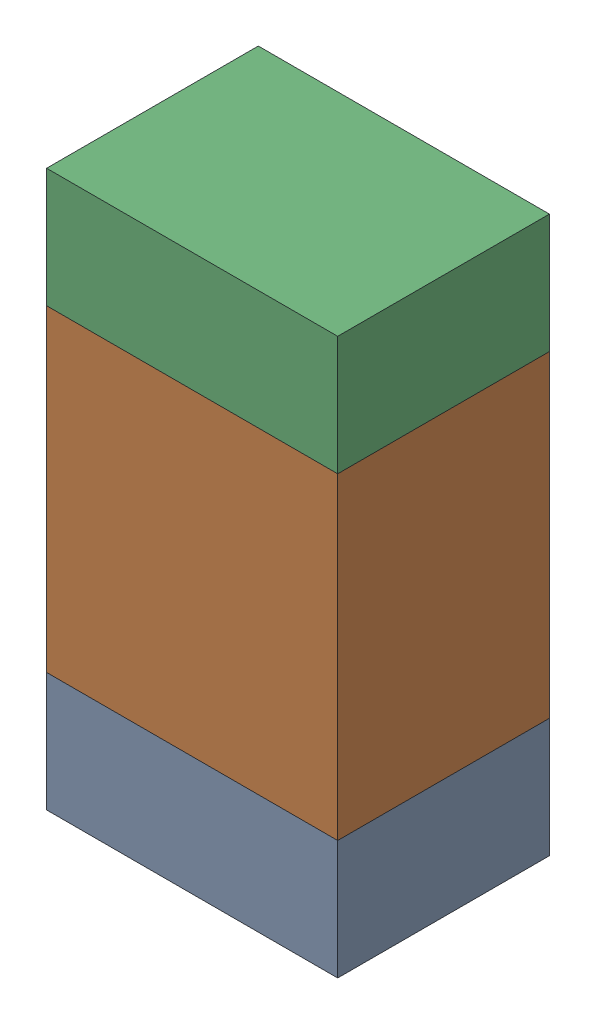
SolidWorks assembly R103_1PCB, configuration Default. Lengths in mm.
Overall size (0.55 1.05 0.4).
6 component instances, 2 part files, 0 mates.
Components (placement in the parent):
- 846483288-1: 846483288 [Default] at (117.5999 114.8876 0) size (0.55 0.22 0.4)
  - Extruded_12-1: Extruded_12 [Default] at origin size (0.55 0.22 0.4)
- 846483424-1: 846483424 [Default] at (117.5999 115.3001 0) size (0.55 0.6 0.4)
  - Extruded_13-1: Extruded_13 [Default] at origin size (0.55 0.6 0.4)
- 846483288-2: 846483288 [Default] at (117.5999 115.7126 0) size (0.55 0.22 0.4)
  - Extruded_12-1: Extruded_12 [Default] at origin size (0.55 0.22 0.4)
